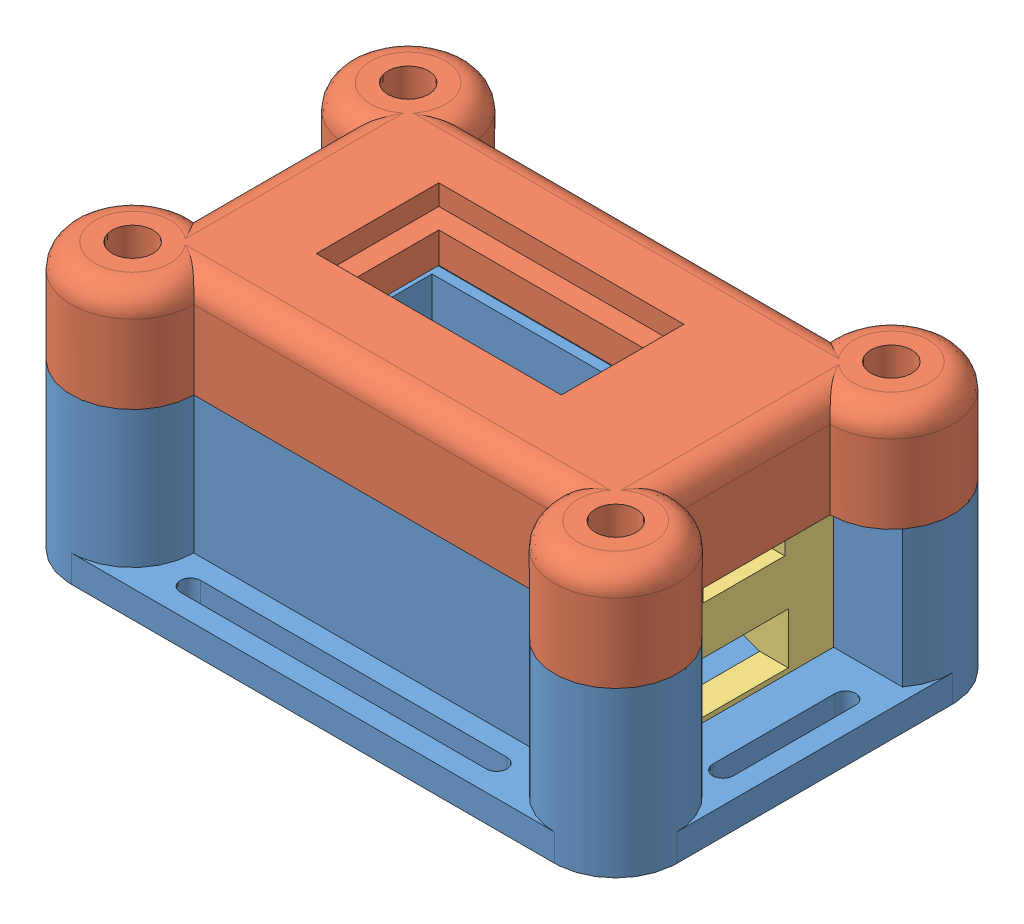
SolidWorks assembly Assy, configuration Default. Lengths in mm.
Overall size (89 39.1 58.5).
3 component instances, 3 part files, 6 mates.
Components (placement in the parent):
- Housing-1: Housing [Default] at origin size (89 24.1 58.5)
- Lid-1: Lid [Default] at (-60 2.1 9) size (89 15 58.5)
- IO_shield-1: IO_shield [Default] at (7.85 -7.95 -13) size (7.7 23 27.5)
Mates (geometry in assembly coordinates):
- Coincident1: coincident aligned: plane of Housing-1 through (-56 2.1 9) normal (0 0 1); plane of Lid-1 through (-51 17.1 9) normal (0 0 1)
- Coincident2: coincident aligned: plane of Housing-1 through (-60 0 0) normal (-1 0 0); plane of Lid-1 through (-60 17.1 0) normal (-1 0 0)
- Width1: width anti-aligned: plane of IO_shield-1 through (5.15 3.55 0.75) normal (0 0 1); plane of IO_shield-1 through (5.15 3.55 -26.75) normal (0 0 -1); plane of Housing-1 through (5 -52.1496 2) normal (0 0 -1); plane of Housing-1 through (5 -52.1496 -28) normal (0 0 1)
- Width2: width anti-aligned: plane of IO_shield-1 through (7.85 -7.95 -13) normal (1 0 0); plane of IO_shield-1 through (5.15 -7.95 -13) normal (-1 0 0); plane of Housing-1 through (8 -52.1496 2) normal (-1 0 0); plane of Housing-1 through (5 -52.1496 2) normal (1 0 0)
- Coincident3: coincident anti-aligned: plane of Housing-1 through (-56 2.1 -27.5) normal (0 1 0); plane of Lid-1 through (-60 2.1 9) normal (0 -1 0)
- Width3: width aligned: plane of IO_shield-1 through (5.15 3.55 0.75) normal (0 1 0); plane of IO_shield-1 through (5.15 -19.45 0.75) normal (0 -1 0); plane of Housing-1 through (-56 -19.5 9) normal (0 1 0); plane of Lid-1 through (-60 3.6 9) normal (0 -1 0)
